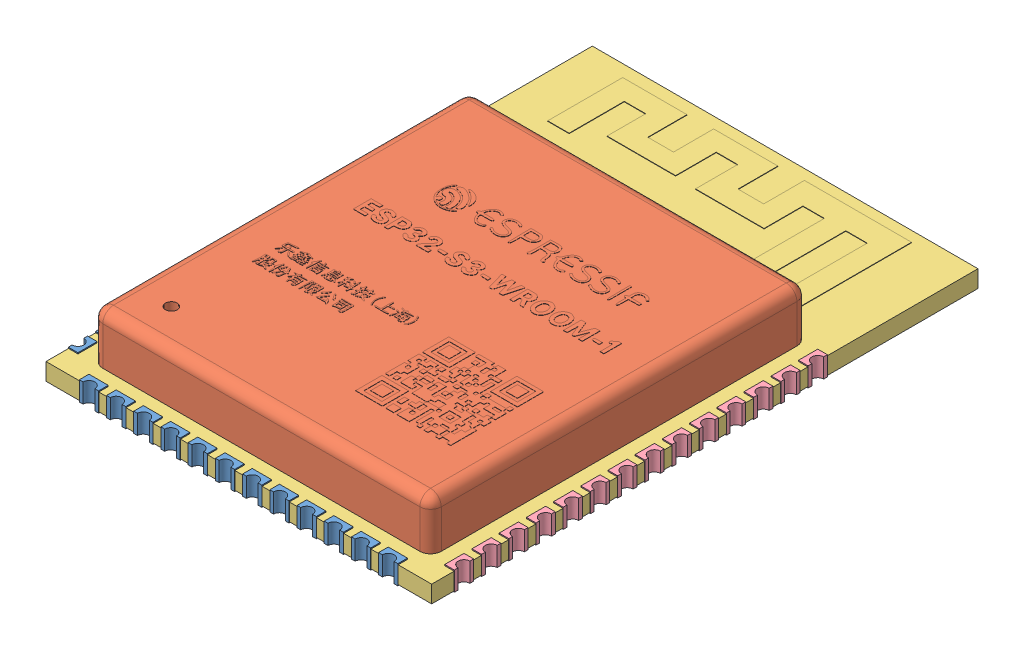
SolidWorks assembly ESP32-S3-WROOM, configuration Default. Lengths in mm.
Overall size (18.02 3.16 25.51).
43 component instances, 4 part files, 0 mates.
Components (placement in the parent):
- ESP32-S3-WROOM.step-1: ESP32-S3-WROOM.step [Default] at origin size (18.02 3.16 25.51)
  - ESP-S3-WROOM_via.step-1: ESP-S3-WROOM_via.step [Default] at (-9.01 -0.05 11.25) size (0.85 0.9 0.9)
  - ESP32-S3-WROOM_shell.step-1: ESP32-S3-WROOM_shell.step [Default] at (0 0.8 2.9) size (15.8 2.31 17.6)
  - ESP32-S3-WROOM_body.step-1: ESP32-S3-WROOM_body.step [Default] at origin size (18 0.84 25.5)
  - ESP-S3-WROOM_via.step-2: ESP-S3-WROOM_via.step [Default] at (-9.01 -0.05 9.98) size (0.85 0.9 0.9)
  - ESP-S3-WROOM_via.step-3: ESP-S3-WROOM_via.step [Default] at (-9.01 -0.05 8.71) size (0.85 0.9 0.9)
  - ESP-S3-WROOM_via.step-4: ESP-S3-WROOM_via.step [Default] at (-9.01 -0.05 7.44) size (0.85 0.9 0.9)
  - ESP-S3-WROOM_via.step-5: ESP-S3-WROOM_via.step [Default] at (-9.01 -0.05 6.17) size (0.85 0.9 0.9)
  - ESP-S3-WROOM_via.step-6: ESP-S3-WROOM_via.step [Default] at (-9.01 -0.05 4.9) size (0.85 0.9 0.9)
  - ESP-S3-WROOM_via.step-7: ESP-S3-WROOM_via.step [Default] at (-9.01 -0.05 3.63) size (0.85 0.9 0.9)
  - ESP-S3-WROOM_via.step-8: ESP-S3-WROOM_via.step [Default] at (-9.01 -0.05 2.36) size (0.85 0.9 0.9)
  - ESP-S3-WROOM_via.step-9: ESP-S3-WROOM_via.step [Default] at (-9.01 -0.05 1.09) size (0.85 0.9 0.9)
  - ESP-S3-WROOM_via.step-10: ESP-S3-WROOM_via.step [Default] at (-9.01 -0.05 -0.18) size (0.85 0.9 0.9)
  - ESP-S3-WROOM_via.step-11: ESP-S3-WROOM_via.step [Default] at (-9.01 -0.05 -1.45) size (0.85 0.9 0.9)
  - ESP-S3-WROOM_via.step-12: ESP-S3-WROOM_via.step [Default] at (-9.01 -0.05 -2.72) size (0.85 0.9 0.9)
  - ESP-S3-WROOM_via.step-13: ESP-S3-WROOM_via.step [Default] at (-9.01 -0.05 -3.99) size (0.85 0.9 0.9)
  - ESP-S3-WROOM_via.step-14: ESP-S3-WROOM_via.step [Default] at (-9.01 -0.05 -5.26) size (0.85 0.9 0.9)
  - ESP-S3-WROOM_via v3(镜像).step-1: ESP-S3-WROOM_via v3(镜像).step [Default] at (9.01 -0.05 11.25) x (-1 0 0) z (0 0 -1) size (0.85 0.9 0.9)
  - ESP-S3-WROOM_via v3(镜像).step-2: ESP-S3-WROOM_via v3(镜像).step [Default] at (9.01 -0.05 9.98) x (-1 0 0) z (0 0 -1) size (0.85 0.9 0.9)
  - ESP-S3-WROOM_via v3(镜像).step-3: ESP-S3-WROOM_via v3(镜像).step [Default] at (9.01 -0.05 8.71) x (-1 0 0) z (0 0 -1) size (0.85 0.9 0.9)
  - ESP-S3-WROOM_via v3(镜像).step-4: ESP-S3-WROOM_via v3(镜像).step [Default] at (9.01 -0.05 7.44) x (-1 0 0) z (0 0 -1) size (0.85 0.9 0.9)
  - ESP-S3-WROOM_via v3(镜像).step-5: ESP-S3-WROOM_via v3(镜像).step [Default] at (9.01 -0.05 6.17) x (-1 0 0) z (0 0 -1) size (0.85 0.9 0.9)
  - ESP-S3-WROOM_via v3(镜像).step-6: ESP-S3-WROOM_via v3(镜像).step [Default] at (9.01 -0.05 4.9) x (-1 0 0) z (0 0 -1) size (0.85 0.9 0.9)
  - ESP-S3-WROOM_via v3(镜像).step-7: ESP-S3-WROOM_via v3(镜像).step [Default] at (9.01 -0.05 3.63) x (-1 0 0) z (0 0 -1) size (0.85 0.9 0.9)
  - ESP-S3-WROOM_via v3(镜像).step-8: ESP-S3-WROOM_via v3(镜像).step [Default] at (9.01 -0.05 2.36) x (-1 0 0) z (0 0 -1) size (0.85 0.9 0.9)
  - ESP-S3-WROOM_via v3(镜像).step-9: ESP-S3-WROOM_via v3(镜像).step [Default] at (9.01 -0.05 1.09) x (-1 0 0) z (0 0 -1) size (0.85 0.9 0.9)
  - ESP-S3-WROOM_via v3(镜像).step-10: ESP-S3-WROOM_via v3(镜像).step [Default] at (9.01 -0.05 -0.18) x (-1 0 0) z (0 0 -1) size (0.85 0.9 0.9)
  - ESP-S3-WROOM_via v3(镜像).step-11: ESP-S3-WROOM_via v3(镜像).step [Default] at (9.01 -0.05 -1.45) x (-1 0 0) z (0 0 -1) size (0.85 0.9 0.9)
  - ESP-S3-WROOM_via v3(镜像).step-12: ESP-S3-WROOM_via v3(镜像).step [Default] at (9.01 -0.05 -2.72) x (-1 0 0) z (0 0 -1) size (0.85 0.9 0.9)
  - ESP-S3-WROOM_via v3(镜像).step-13: ESP-S3-WROOM_via v3(镜像).step [Default] at (9.01 -0.05 -3.99) x (-1 0 0) z (0 0 -1) size (0.85 0.9 0.9)
  - ESP-S3-WROOM_via v3(镜像).step-14: ESP-S3-WROOM_via v3(镜像).step [Default] at (9.01 -0.05 -5.26) x (-1 0 0) z (0 0 -1) size (0.85 0.9 0.9)
  - ESP-S3-WROOM_via.step-15: ESP-S3-WROOM_via.step [Default] at (-6.985 -0.05 12.76) x (0 0 -1) z (1 0 0) size (0.85 0.9 0.9)
  - ESP-S3-WROOM_via.step-16: ESP-S3-WROOM_via.step [Default] at (-5.715 -0.05 12.76) x (0 0 -1) z (1 0 0) size (0.85 0.9 0.9)
  - ESP-S3-WROOM_via.step-17: ESP-S3-WROOM_via.step [Default] at (-4.445 -0.05 12.76) x (0 0 -1) z (1 0 0) size (0.85 0.9 0.9)
  - ESP-S3-WROOM_via.step-18: ESP-S3-WROOM_via.step [Default] at (-3.175 -0.05 12.76) x (0 0 -1) z (1 0 0) size (0.85 0.9 0.9)
  - ESP-S3-WROOM_via.step-19: ESP-S3-WROOM_via.step [Default] at (-1.905 -0.05 12.76) x (0 0 -1) z (1 0 0) size (0.85 0.9 0.9)
  - ESP-S3-WROOM_via.step-20: ESP-S3-WROOM_via.step [Default] at (-0.635 -0.05 12.76) x (0 0 -1) z (1 0 0) size (0.85 0.9 0.9)
  - ESP-S3-WROOM_via.step-21: ESP-S3-WROOM_via.step [Default] at (0.635 -0.05 12.76) x (0 0 -1) z (1 0 0) size (0.85 0.9 0.9)
  - ESP-S3-WROOM_via.step-22: ESP-S3-WROOM_via.step [Default] at (1.905 -0.05 12.76) x (0 0 -1) z (1 0 0) size (0.85 0.9 0.9)
  - ESP-S3-WROOM_via.step-23: ESP-S3-WROOM_via.step [Default] at (3.175 -0.05 12.76) x (0 0 -1) z (1 0 0) size (0.85 0.9 0.9)
  - ESP-S3-WROOM_via.step-24: ESP-S3-WROOM_via.step [Default] at (4.445 -0.05 12.76) x (0 0 -1) z (1 0 0) size (0.85 0.9 0.9)
  - ESP-S3-WROOM_via.step-25: ESP-S3-WROOM_via.step [Default] at (5.715 -0.05 12.76) x (0 0 -1) z (1 0 0) size (0.85 0.9 0.9)
  - ESP-S3-WROOM_via.step-26: ESP-S3-WROOM_via.step [Default] at (6.985 -0.05 12.76) x (0 0 -1) z (1 0 0) size (0.85 0.9 0.9)
